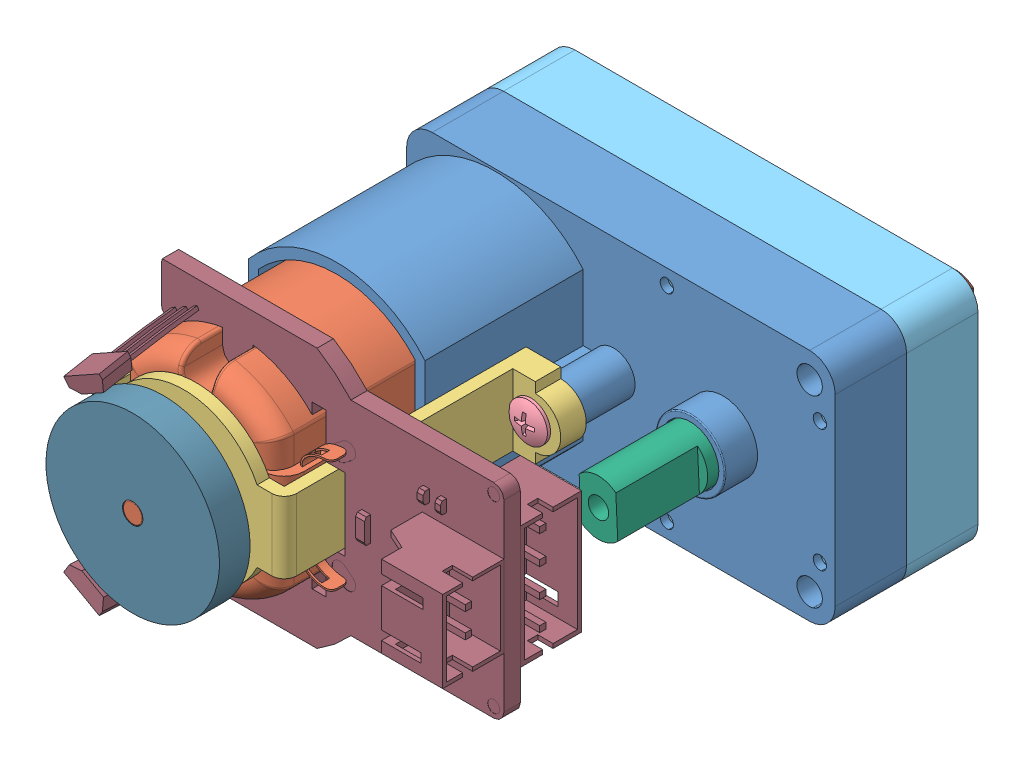
SolidWorks assembly TT_ANGLE_MOTOR_WITH_ENCODER, configuration По умолчанию. Lengths in mm.
Overall size (49.84 25.87 58.37).
16 component instances, 14 part files, 0 mates.
Components (placement in the parent):
- 1-1: 1 [По умолчанию] at (18.7579 -8.136 0) size (47.1 23 22.5)
- 2-1: 2 [По умолчанию] at (-11.2666 2.0594 10.6) size (20.08 20 41.9)
- 3-1: 3 [По умолчанию] at (-11.2666 2.0594 36.3) x (-1 0 0) z (0 0 1) size (29.11 16 24.9)
- 4-1: 4 [По умолчанию] at (-22.9166 2.0594 5.4) x (0 0 -1) z (1 0 0) size (10.55 3.86 3.98)
- 4-2: 4 [По умолчанию] at (0.3834 2.0594 5.4) x (0 0 -1) z (1 0 0) size (10.55 3.86 3.98)
- 5-1: 5 [По умолчанию] at (18.7579 -8.136 0) x (-1 0 0) z (0 0 -1) size (42 23 15.3)
- 6-1: 6 [По умолчанию] at (11.0834 2.0594 7) x (0.998872 0.047482 0) z (0 0 1) size (5.4 5.4 29.2)
- 7-1: 7 [По умолчанию] at (-0.3166 2.0594 3.6) x (-0.926164 -0.377122 0) z (0 0 -1) size (18.6 18.6 4.5)
- 8-1: 8 [По умолчанию] at (-0.3166 2.0594 -8.2) x (-0.150609 -0.988593 0) z (0 0 1) size (2 2 14.4)
- 9-1: 9 [По умолчанию] at (11.0834 2.0594 1.1) x (-0.822827 -0.568292 0) z (0 0 -1) size (18.6 18.6 4.5)
- 10-1: 10 [По умолчанию] at (-0.3166 2.0594 -1.4) x (-0.973048 -0.230602 0) z (0 0 -1) size (14.65 14.7 4.5)
- 11-1: 11 [По умолчанию] at (11.0834 2.0594 -3.1) x (-0.998872 -0.047482 0) z (0 0 -1) size (14.65 14.7 12.7)
- 12-1: 12 [По умолчанию] at (-8.3166 -6.9406 7) x (0 0 1) z (-1 0 0) size (14.6 4.05 4.15)
- 12-2: 12 [По умолчанию] at (-8.3166 11.0594 7) x (0 0 1) z (-1 0 0) size (14.6 4.05 4.15)
- 13-1: 13 [По умолчанию] at (-11.2666 2.0594 30.6) x (0 1 0) z (0 0 1) size (25.5 33.59 17.97)
- 14-1: 14 [По умолчанию] at (-11.2666 2.0594 39.5) x (0.099647 -0.995023 0) z (0 0 1) size (17 17 3)
